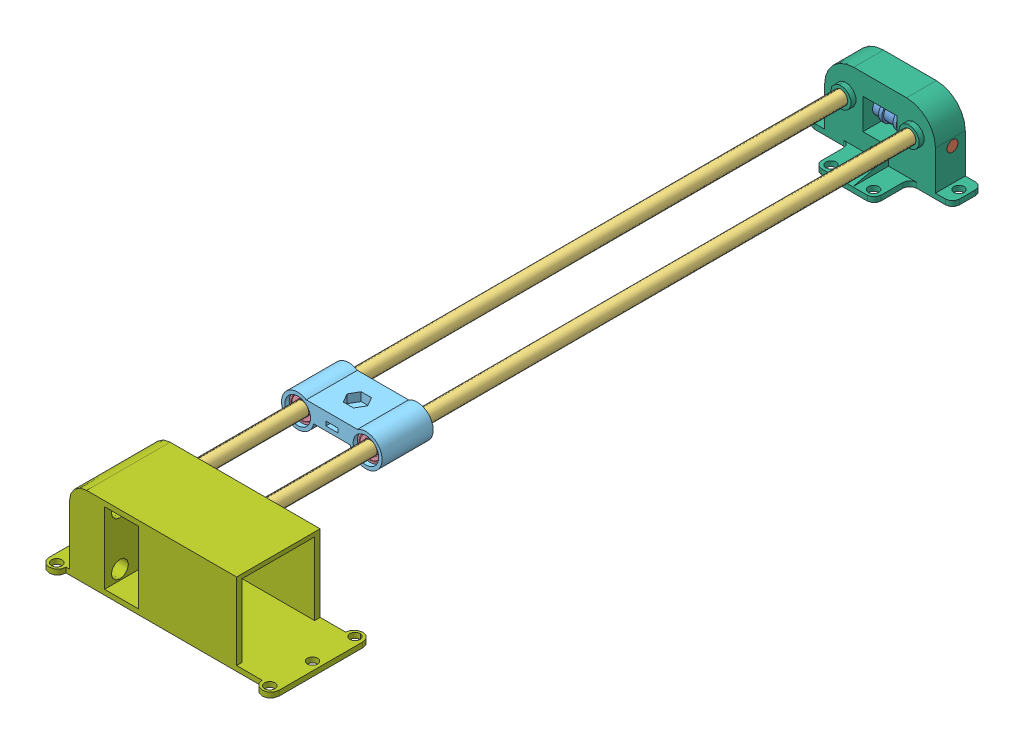
SolidWorks assembly Sestava1, configuration Default. Lengths in mm.
Overall size (135 48 527.03).
9 component instances, 7 part files, 15 mates.
Components (placement in the parent):
- Valec-1: Valec [Default] at (0.1941 22 -1.25) x (1 0 0) z (0 0.002 0.999998) size (19.5 11.7 11.7)
- Osa-1: Osa [Default] at (-17.5 22 -1.25) x (0 0.093545 -0.995615) z (0 -0.995615 -0.093545) size (6.55 50 6.55)
- TYČ POJEZD-1: TYČ POJEZD [Default] at (-20 27 404.75) x (1 0 0) z (0 1 0) size (8 400 8)
- TYČ POJEZD-2: TYČ POJEZD [Default] at (20 27 404.75) x (1 0 0) z (0 1 0) size (8 400 8)
- LOŽISKO POSUVNE-1: LOŽISKO POSUVNE [Default] at (-20 27 303.8939) size (15 15 24)
- LOŽISKO POSUVNE-2: LOŽISKO POSUVNE [Default] at (20 27 303.8939) x (0.938936 -0.344093 0) z (0 0 1) size (15 15 24)
- pojizda_hovadina2-1: pojizda_hovadina2 [Výchozí] at (15 30.0777 300.3939) x (1 0 0) z (0 1 0) size (59 30 19)
- UCHYT REMEN3-2: UCHYT REMEN3 [Default] at origin size (85 43 38.5)
- MOTOR_drzak-1: MOTOR_drzak [Default] at (25 3 429.25) x (0 0 1) z (1 0 0) size (156.22 48 135)
Mates (geometry in assembly coordinates):
- Soustředná6: concentric aligned: cylinder of TYČ POJEZD-2 through (20 27 4.75) axis (0 0 1) radius 4; cylinder of LOŽISKO POSUVNE-2 through (20 27 303.8929) axis (0 0 1) radius 4
- Soustředná7: concentric aligned: cylinder of TYČ POJEZD-1 through (-20 27 4.75) axis (0 0 1) radius 4; cylinder of LOŽISKO POSUVNE-1 through (-20 27 303.8929) axis (0 0 1) radius 4
- Sjednocená4: coincident aligned: plane of LOŽISKO POSUVNE-1 through (-20 27 327.8939) normal (0 0 1); plane of LOŽISKO POSUVNE-2 through (20 27 327.8939) normal (0 0 1)
- Soustředná9: concentric anti-aligned: cylinder of LOŽISKO POSUVNE-2 through (20 27 327.8939) axis (0 0 -1) radius 7.5; cylinder of pojizda_hovadina2-1 through (20 27 273.5238) axis (0 0 1) radius 7.5
- Soustředná10: concentric anti-aligned: cylinder of LOŽISKO POSUVNE-1 through (-20 27 327.8939) axis (0 0 -1) radius 7.5; cylinder of pojizda_hovadina2-1 through (-20 27 273.5238) axis (0 0 1) radius 7.5
- Vzdálenost3: distance = 2.5 mm aligned: plane of LOŽISKO POSUVNE-1 through (-20 27 327.8939) normal (0 0 1); plane of pojizda_hovadina2-1 through (15 35.0777 330.3939) normal (0 0 1)
- Sjednocená5: coincident anti-aligned: plane of TYČ POJEZD-2 through (20 27 4.75) normal (0 0 -1); plane of UCHYT REMEN3-2 through (0 0 4.75) normal (0 0 1)
- Soustředná11: concentric anti-aligned: cylinder of TYČ POJEZD-2 through (20 27 4.75) axis (0 0 1) radius 4; cylinder of UCHYT REMEN3-2 through (20 27 11.75) axis (0 0 -1) radius 4.1
- Soustředná12: concentric anti-aligned: cylinder of Osa-1 through (12.5 22 -1.25) axis (-1 0 0) radius 3.1; cylinder of UCHYT REMEN3-2 through (-17.5 22 -1.25) axis (1 0 0) radius 3.25
- Sjednocená6: coincident anti-aligned: plane of Osa-1 through (-17.5 22 -1.25) normal (-1 0 0); plane of UCHYT REMEN3-2 through (-17.5 22 -1.25) normal (1 0 0)
- Soustředná13: concentric aligned: cylinder of Valec-1 through (0.1941 22 -1.25) axis (-1 0 0) radius 3.5; cylinder of Osa-1 through (12.5 22 -1.25) axis (-1 0 0) radius 3.1
- Soustředná14: concentric anti-aligned: cylinder of TYČ POJEZD-1 through (-20 27 4.75) axis (0 0 1) radius 4; cylinder of UCHYT REMEN3-2 through (-20 27 11.75) axis (0 0 -1) radius 4.1
- Soustředná15: concentric aligned: cylinder of TYČ POJEZD-2 through (20 27 4.75) axis (0 0 1) radius 4; cylinder of MOTOR_drzak-1 through (20 27 397.75) axis (0 0 1) radius 4.1
- Soustředná16: concentric aligned: cylinder of TYČ POJEZD-1 through (-20 27 4.75) axis (0 0 1) radius 4; cylinder of MOTOR_drzak-1 through (-20 27 397.75) axis (0 0 1) radius 4.1
- Sjednocená8: coincident anti-aligned: plane of TYČ POJEZD-1 through (-20 27 404.75) normal (0 0 1); circle of MOTOR_drzak-1
